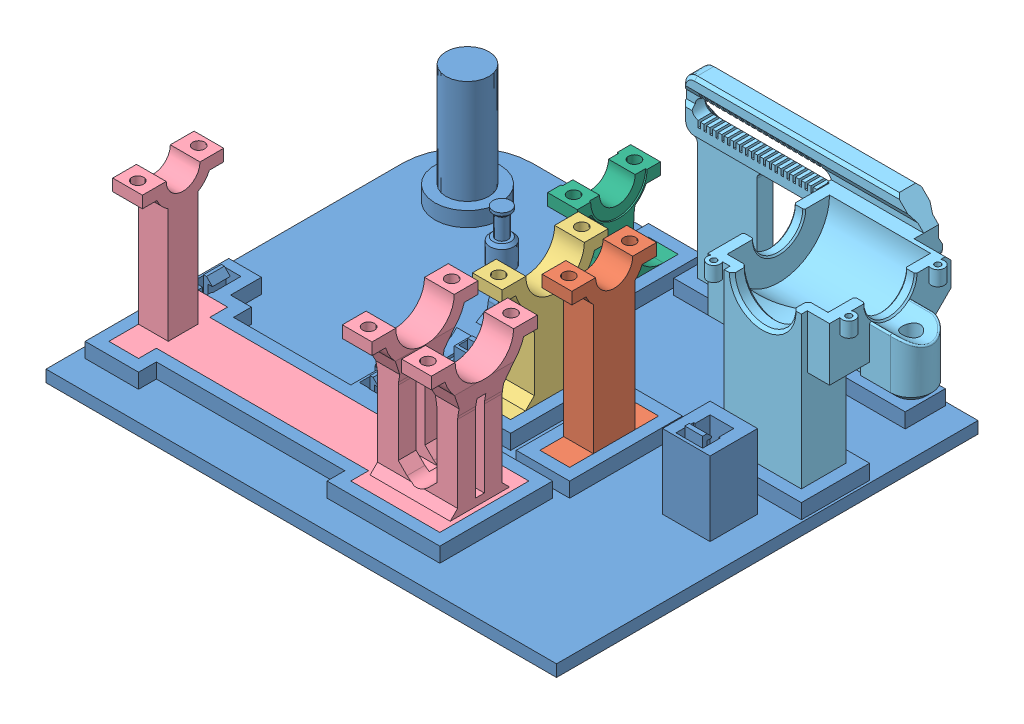
SolidWorks assembly Сборка1, configuration По умолчанию. Lengths in mm.
Overall size (188.72 68 149).
6 component instances, 6 part files, 15 mates.
Components (placement in the parent):
- base-1: base [По умолчанию] at origin size (172 44 149)
- gear_holder_1-1: gear_holder_1 [По умолчанию] at (99.9004 60 50.4847) x (0 0 1) z (-1 0 0) size (30 56 10)
- gear_holder_3-1: gear_holder_3 [По умолчанию] at (71 48.25 46.4812) x (0 0 1) z (-1 0 0) size (35.7 44.25 10)
- gear_holder_4-1: gear_holder_4 [По умолчанию] at (82 56 91.3163) x (0 0 1) z (-1 0 0) size (35.7 52 111.5)
- diff_cap-1: diff_cap [По умолчанию] at (132.2155 60 10.2373) x (1 0 0) z (0 -1 0) size (104.5 51.7 64)
- gearR12 holder-1: gearR12 holder [По умолчанию] at (51 39 5) x (0 0 -1) z (1 0 0) size (40 35 10)
Mates (geometry in assembly coordinates):
- Совпадение1: coincident: plane of base-1 through (67 9 100.3163) normal (0 0 -1); plane of gear_holder_4-1 through (-4.5 9 100.3163) normal (0 0 1)
- Совпадение2: coincident: plane of base-1 through (0 4 0) normal (0 1 0); plane of gear_holder_4-1 through (67 4 76.3163) normal (0 -1 0)
- Совпадение3: coincident anti-aligned: plane of base-1 through (67 9 106.3163) normal (1 0 0); plane of gear_holder_4-1 through (67 56 91.3163) normal (-1 0 0)
- Совпадение4: coincident: plane of base-1 through (66 9 61.4812) normal (1 0 0); plane of gear_holder_3-1 through (66 48.25 46.4812) normal (-1 0 0)
- Совпадение5: coincident: plane of base-1 through (0 4 0) normal (0 1 0); plane of gear_holder_3-1 through (66 4 46.4812) normal (0 -1 0)
- Совпадение6: coincident anti-aligned: plane of base-1 through (66 9 31.4812) normal (0 0 1); plane of gear_holder_3-1 through (66 48.25 31.4812) normal (0 0 -1)
- Совпадение7: coincident: plane of base-1 through (89.9004 9 35.4847) normal (1 0 0); plane of gear_holder_1-1 through (89.9004 60 50.4847) normal (-1 0 0)
- Совпадение8: coincident: plane of base-1 through (0 4 0) normal (0 1 0); plane of gear_holder_1-1 through (89.9004 4 35.4847) normal (0 -1 0)
- Совпадение9: coincident anti-aligned: plane of base-1 through (89.9004 9 65.4847) normal (0 0 -1); plane of gear_holder_1-1 through (89.9004 9 65.4847) normal (0 0 1)
- Совпадение10: coincident: plane of base-1 through (145.2155 9 17.7373) normal (-1 0 0); plane of diff_cap-1 through (145.2155 42 32.7373) normal (1 0 0)
- Совпадение11: coincident: plane of base-1 through (145.2155 9 32.7373) normal (0 0 -1); plane of diff_cap-1 through (119.2155 42 32.7373) normal (0 0 1)
- Совпадение12: coincident anti-aligned: plane of base-1 through (0 4 0) normal (0 1 0); plane of diff_cap-1 through (132.2155 4 10.2373) normal (0 -1 0)
- Совпадение13: coincident: plane of base-1 through (46 9 -15) normal (0 0 1); plane of gearR12 holder-1 through (56 39 -15) normal (0 0 -1)
- Совпадение14: coincident: plane of base-1 through (56 9 -15) normal (-1 0 0); plane of gearR12 holder-1 through (56 39 5) normal (1 0 0)
- Совпадение15: coincident anti-aligned: plane of base-1 through (0 4 0) normal (0 1 0); plane of gearR12 holder-1 through (56 4 5) normal (0 -1 0)
